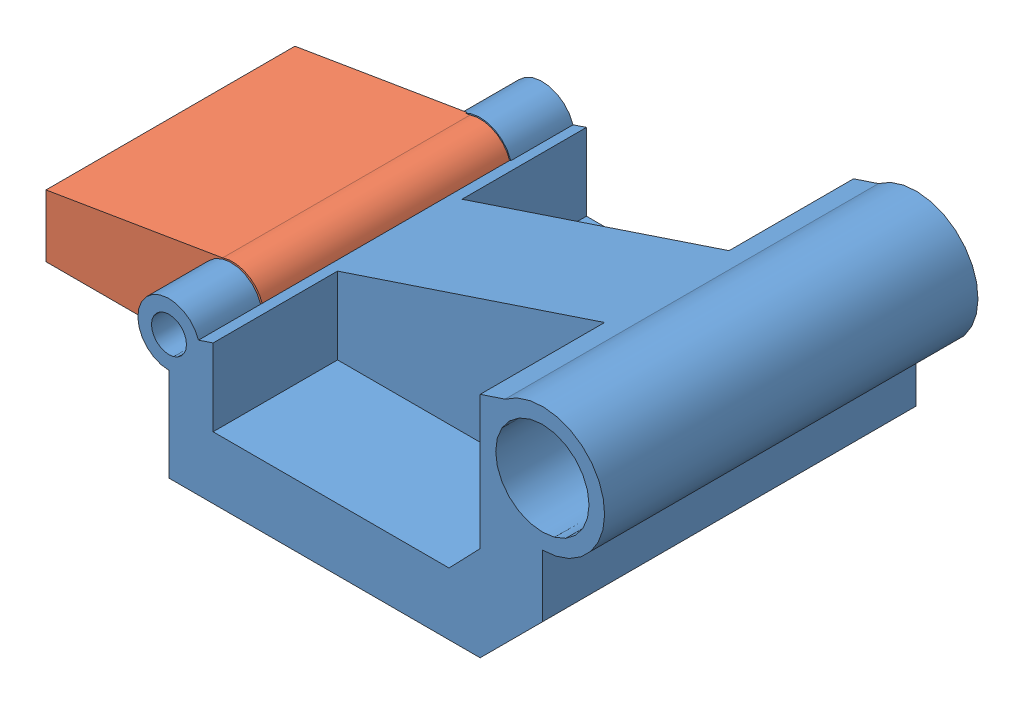
SolidWorks assembly Assem1, configuration Default. Lengths in mm.
Overall size (101.6 50.8 51.4).
2 component instances, 2 part files, 1 mates.
Components (placement in the parent):
- Part2-1: Part2 [Default] at (38.0336 47.4537 81.7111) size (101.6 50.8 51.4)
- Part3-1: Part3 [Default] at (39.0456 40.2672 94.261) size (22.22 9.52 25.4)
Mates (geometry in assembly coordinates):
- Concentric1: concentric: cylinder of Part2-1 through (63.4336 61.5583 100.7611) axis (0 0 1) radius 1.786; point of Part3-1
